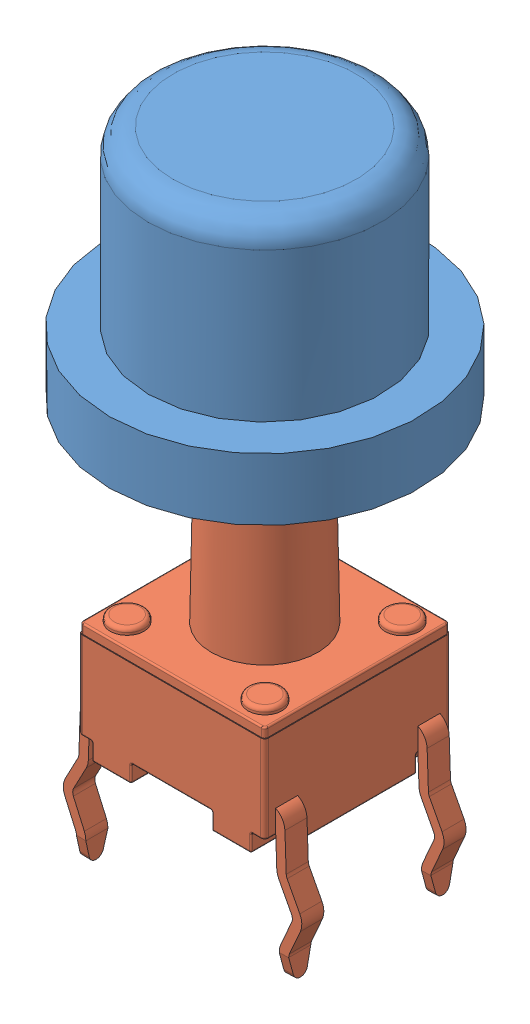
SolidWorks assembly button_construct, configuration По умолчанию. Lengths in mm.
Overall size (10 20.88 10).
2 component instances, 2 part files, 3 mates.
Components (placement in the parent):
- button-1: button [По умолчанию] at origin size (10 7.6 10)
- tactileswitch-long-1: tactileswitch-long [Default] at (0 -14.5064 0) size (7.69 16.48 6.01)
Mates (geometry in assembly coordinates):
- Параллельность1: parallel: plane of button-1 through (0 -4.6 0) normal (0 -1 0); plane of tactileswitch-long-1 through (0 -18.8828 0) normal (0 1 0)
- Концентричный1: concentric: circle of button-1; circle of tactileswitch-long-1
- Совпадение3: coincident aligned: plane of button-1 through (0 -1.4 0) normal (0 1 0); plane of tactileswitch-long-1 through (0 -1.4 0) normal (0 1 0)
